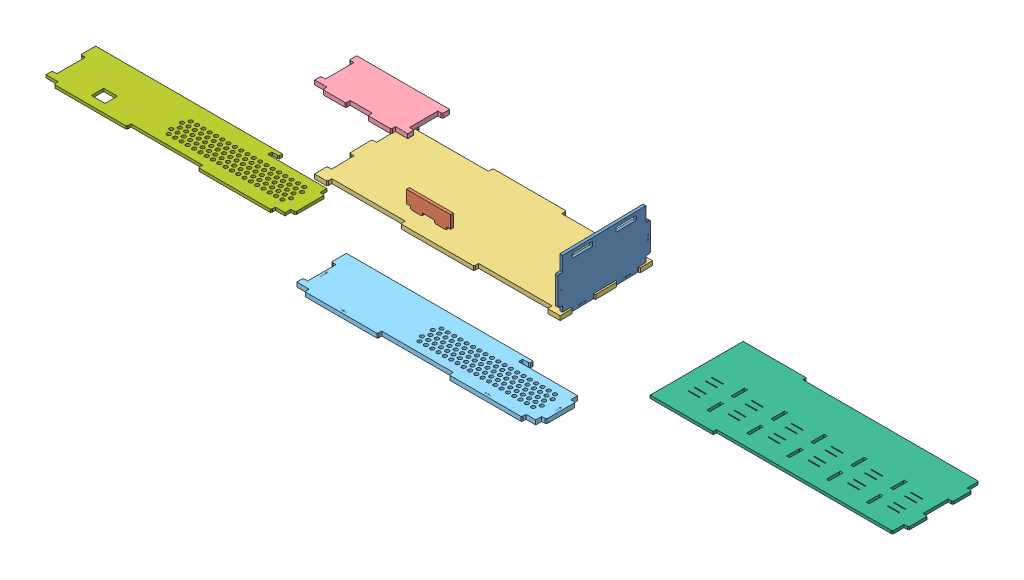
SolidWorks assembly Assem1, configuration Default. Lengths in mm.
Overall size (769.45 137.64 206.78).
7 component instances, 7 part files, 3 mates.
Components (placement in the parent):
- Back Wall, Laser Cut Box, Masonite (0.17in), Type 1-1: Back Wall, Laser Cut Box, Masonite (0.17in), Type 1 [Default] at (-75.4214 45.0942 105.1378) x (0.00865 -0.008802 0.999924) z (-0.008802 -0.999923 -0.008726) size (93.65 2.86 54.32)
- DIVIDER-1: DIVIDER [Default] at (-186.0151 66.2496 168.5355) size (44.45 15.56 2.86)
- Floor,  Laser Cut Box, Masonite (0.17in), Type 1-1: Floor,  Laser Cut Box, Masonite (0.17in), Type 1 [Default] at (-196.5135 16.8357 105.619) x (0.999924 -0.008726 -0.008727) z (0.00865 -0.008802 0.999924) size (245.11 4.32 93.65)
- Front Wall, Laser Cut Box, Masonite (0.17in), Type 1-1: Front Wall, Laser Cut Box, Masonite (0.17in), Type 1 [Default] at (-250.0663 121.1176 150.1449) size (93.65 4.32 46.57)
- Left Wall, Laser Cut Box, Masonite (0.17in), Type 1-1: Left Wall, Laser Cut Box, Masonite (0.17in), Type 1 [Default] at (-140.5616 -12.2073 201.9508) size (245.11 4.32 54.32)
- Lid_v2, Laser Cut Box, Masonite (0.17in), Type 1-1: Lid_v2, Laser Cut Box, Masonite (0.17in), Type 1 [Default] at (164.5989 17.9988 129.6213) size (245.11 2.86 93.65)
- Right Wall, Laser Cut Box, Masonite (0.17in), Type 1-1: Right Wall, Laser Cut Box, Masonite (0.17in), Type 1 [Default] at (-359.7427 76.9517 235.186) size (245.11 2.86 54.32)
Mates (geometry in assembly coordinates):
- Coincident1: coincident anti-aligned: plane of Back Wall, Laser Cut Box, Masonite (0.17in), Type 1-1 through (-78.2787 45.1191 105.1627) normal (-0.999924 0.008726 0.008727); plane of Floor,  Laser Cut Box, Masonite (0.17in), Type 1-1 through (-78.4411 15.705 115.964) normal (0.999924 -0.008726 -0.008727)
- Coincident3: coincident aligned: plane of Back Wall, Laser Cut Box, Masonite (0.17in), Type 1-1 through (-102.6142 16.3141 70.673) normal (-0.008802 -0.999923 -0.008726); plane of Floor,  Laser Cut Box, Masonite (0.17in), Type 1-1 through (-196.5135 16.8357 105.619) normal (-0.008802 -0.999923 -0.008726)
- Coincident4: coincident anti-aligned: plane of Back Wall, Laser Cut Box, Masonite (0.17in), Type 1-1 through (-102.5762 20.6317 70.7106) normal (-0.00865 0.008802 -0.999924); plane of Floor,  Laser Cut Box, Masonite (0.17in), Type 1-1 through (-74.263 16.0656 70.4255) normal (0.00865 -0.008802 0.999924)
